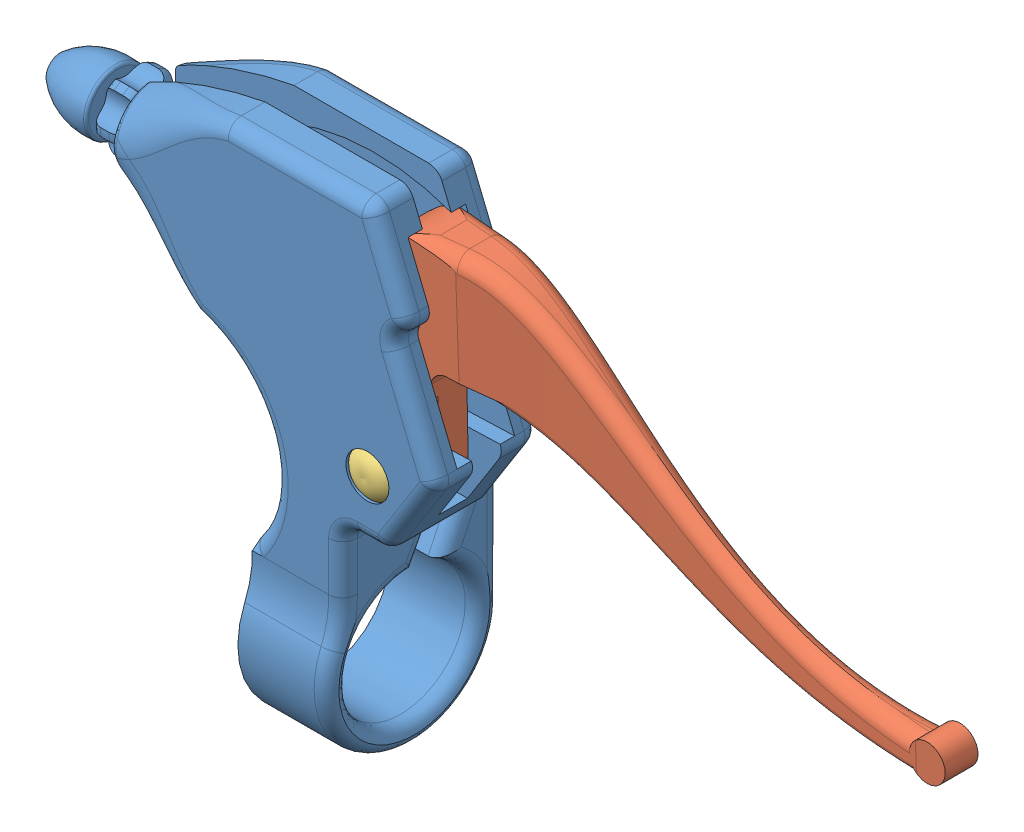
SolidWorks assembly Assem1, configuration Default. Lengths in mm.
Overall size (191.94 110.71 36.94).
4 component instances, 3 part files, 9 mates.
Components (placement in the parent):
- Break1-1: Break1 [Default] at (-31.634 -60.6608 19.5968) size (91.08 110.68 36.94)
- Lever-3: Lever [Default] at (-9.5632 -8.4092 30.7371) x (0.999349 0.036085 0) z (0 0 1) size (121.93 60.86 23.2)
- nut-1: nut [Default] at (-7.8474 -11.9015 34.4063) x (1 0 0) z (0 -1 0) size (9.22 12.37 9.22)
- nut-2: nut [Default] at (-7.8474 -11.9015 32.3499) x (0 -1 0) z (1 0 0) size (9.22 12.37 9.22)
Mates (geometry in assembly coordinates):
- Concentric3: concentric aligned: cylinder of Break1-1 through (-7.8474 -11.9015 -1.044) axis (0 0 1) radius 2.3051; cylinder of Lever-3 through (-7.8474 -11.9015 30.3047) axis (0 0 1) radius 2.3051
- Width2: width aligned: plane of Lever-3 through (-0.9901 16.1281 30.3047) normal (0 0 -1); plane of Lever-3 through (-0.9901 16.1281 36.4515) normal (0 0 1); plane of Break1-1 through (-66.9013 -25.768 36.4515) normal (0 0 -1); plane of Break1-1 through (-66.9013 -25.768 30.3047) normal (0 0 1)
- Concentric4: concentric anti-aligned: cylinder of Break1-1 through (-7.8474 -11.9015 -1.044) axis (0 0 1) radius 2.3051; cylinder of nut-1 through (-7.8474 -11.9015 33.2244) axis (0 0 -1) radius 2.4587
- Coincident4: coincident anti-aligned: plane of Break1-1 through (-7.8474 -11.9015 43.9813) normal (0 0 1); plane of nut-1 through (-5.3886 -11.9015 43.9813) normal (0 0 -1)
- Concentric5: concentric: cylinder of Break1-1 through (-7.8474 -11.9015 -1.044) axis (0 0 1) radius 2.3051; cylinder of nut-2 through (-7.8474 -11.9015 33.5317) axis (0 0 1) radius 2.4587
- Coincident5: coincident: plane of Break1-1 through (-7.8474 -11.9015 22.7748) normal (0 0 -1); plane of nut-2 through (-10.1185 -12.8433 22.7748) normal (0 0 1)
- Parallel2: parallel anti-aligned: plane of Break1-1 through (-26.1 -7.2556 30.3047) normal (-0.036085 0.999349 0); plane of Lever-3 through (-0.913 2.6865 27.2313) normal (0.036085 -0.999349 0)
- Parallel3: parallel anti-aligned: plane of nut-1 through (-7.8474 -11.9015 34.4063) normal (0 -1 0)
- Coincident7: coincident aligned: plane of nut-1 through (-7.8474 -11.9015 34.4063) normal (0 -1 0); plane of nut-2 through (-7.8474 -11.9015 32.3499) normal (0 -1 0)
